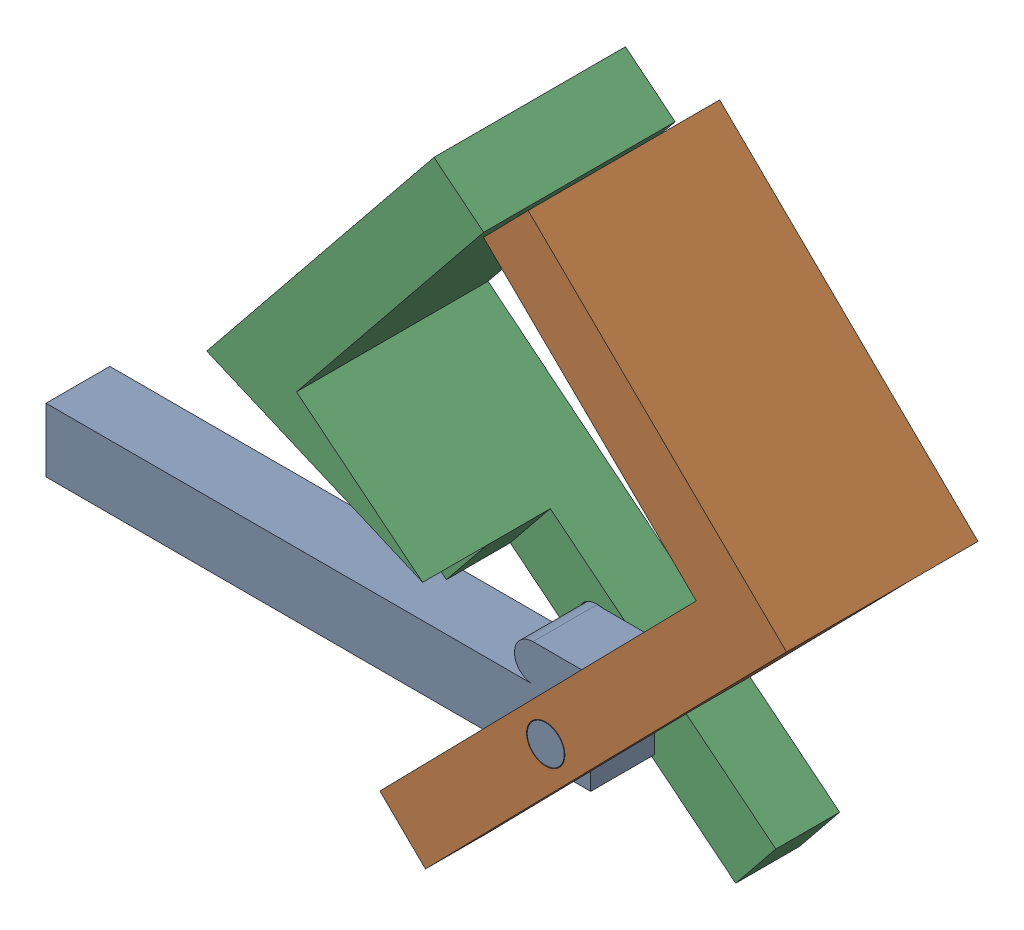
SolidWorks assembly 装配体40SLDASM, configuration 默认. Lengths in mm.
Overall size (63.3 51.73 15).
3 component instances, 2 part files, 4 mates.
Components (placement in the parent):
- center-1: center [默认] at origin size (45.59 7.9 15)
- left-1: left [默认] at (1.46 -1.0612 10) x (-0.999948 -0.010157 0) z (0 0 -1) size (32.11 48.61 15)
- left-2: left [默认] at (4.6325 -0.5275 -5) x (0.994379 0.105881 0) z (0 0 1) size (32.11 48.61 15)
Mates (geometry in assembly coordinates):
- 重合1: coincident anti-aligned: plane of center-1 through (0 0 5) normal (0 0 1); plane of left-1 through (1.46 -1.0612 5) normal (0 0 -1)
- 同心1: concentric aligned: cylinder of center-1 through (6 0 5) axis (0 0 -1) radius 1.45; circle of left-1
- 重合2: coincident anti-aligned: plane of center-1 through (0 0 0) normal (0 0 -1); plane of left-2 through (4.6325 -0.5275 0) normal (0 0 1)
- 同心2: concentric anti-aligned: cylinder of center-1 through (0 0 5) axis (0 0 -1) radius 1.45; cylinder of left-2 through (0 0 -5) axis (0 0 1) radius 1.5
